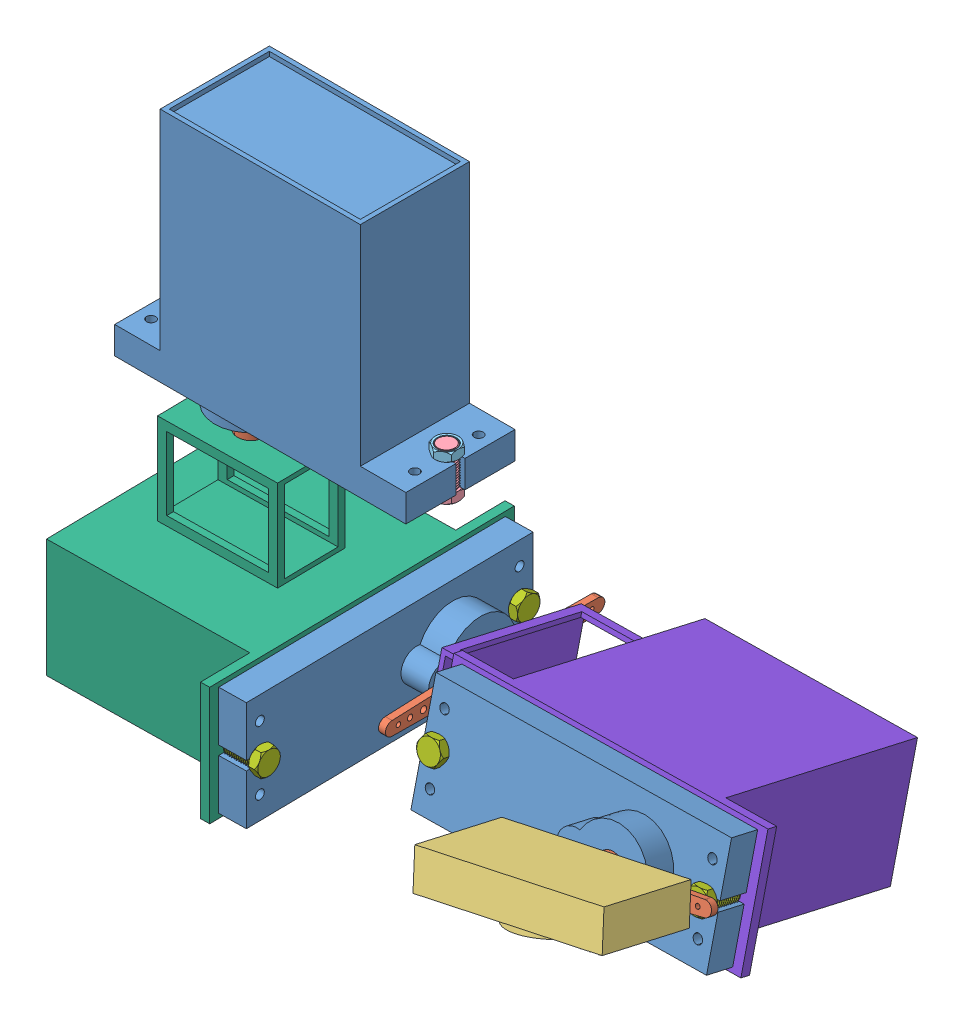
SolidWorks assembly ggimbal_assem, configuration Default. Lengths in mm.
Overall size (73.77 56.88 42.41).
21 component instances, 8 part files, 41 mates.
Components (placement in the parent):
- servo_body-1: servo_body [Default] at (-27.6645 3.5088 -0.9935) x (-0.015077 -0.232674 -0.972438) z (0.99988 0 -0.015503) size (31 12 32)
- servo_blade-1: servo_blade [Default] at (-9.4028 7.5806 15.7451) x (0.984245 0.167894 -0.055432) z (0.015077 0.232674 0.972438) size (24.5 3 2.5)
- camera_scaled-1: camera_scaled [Default] at (-9.3783 7.9587 17.3253) x (0.984245 0.167894 -0.055432) z (0.015077 0.232674 0.972438) size (20 5 10)
- servo_blade-2: servo_blade [Default] at (-40.6704 3.3925 -1.2782) x (0.015503 0 0.99988) z (0.99988 0 -0.015503) size (24.5 3 2.5)
- servo_body-2: servo_body [Default] at (-57.8893 3.3925 16.9909) x (-0.99988 0 0.015503) z (-0.015503 0 -0.99988) size (31 12 32)
- servo_blade-3: servo_blade [Default] at (-58.5598 22.3925 6) x (1 0 0) z (0 -1 0) size (24.5 3 2.5)
- servo_body-3: servo_body [Default] at (-40.5598 39.8925 6) x (0 1 0) z (-1 0 0) size (31 12 32)
- servo_bolt-3: servo_bolt [Default] at (-37.0598 25.3925 6) x (0 0 -1) z (0 -1 0) size (3.17 2.5 5.1)
- servo_bolt-4: servo_bolt [Default] at (-66.0598 25.3925 6) x (0 0 -1) z (0 -1 0) size (3.17 2.5 5.1)
- servo_nut-3: servo_nut [Default] at (-37.0598 29.3925 6) x (0 0 1) z (0 -1 0) size (3.17 2.62 1.08)
- servo_nut-4: servo_nut [Default] at (-66.0598 29.3925 6) x (-1 0 0) z (0 -1 0) size (3.17 2.62 1.08)
- servo_housing1-1: servo_housing1 [Default] at (-69.5584 3.3925 6.1705) x (0 -1 0) z (0.99988 0 -0.015503) size (23 34 23)
- servo_bolt_long-1: servo_bolt_long [Default] at (-43.3368 3.3925 20.2657) x (0.015503 0 0.99988) z (0.99988 0 -0.015503) size (3.17 2.5 6.11)
- servo_bolt_long-2: servo_bolt_long [Default] at (-43.7863 3.3925 -8.7308) x (0 1 0) z (0.99988 0 -0.015503) size (3.17 2.5 6.11)
- servo_nut-5: servo_nut [Default] at (-48.3362 3.3925 20.3432) x (0 1 0) z (0.99988 0 -0.015503) size (3.17 2.62 1.08)
- servo_nut-6: servo_nut [Default] at (-48.7857 3.3925 -8.6533) x (0 1 0) z (0.99988 0 -0.015503) size (3.17 2.62 1.08)
- servo_housing2-1: servo_housing2 [Default] at (-16.8392 0.8331 -12.3471) x (0.003607 -0.972555 0.232646) z (0.015077 0.232674 0.972438) size (13 38.5 23)
- servo_bolt_long-3: servo_bolt_long [Default] at (-30.9454 6.8826 13.1611) x (0.99988 0 -0.015503) z (0.015077 0.232674 0.972438) size (3.17 2.5 6.11)
- servo_bolt_long-4: servo_bolt_long [Default] at (-1.9489 6.8826 12.7115) x (0.99988 0 -0.015503) z (0.015077 0.232674 0.972438) size (3.17 2.5 6.11)
- servo_nut-7: servo_nut [Default] at (-31.0208 5.7192 8.2989) x (0.99988 0 -0.015503) z (0.015077 0.232674 0.972438) size (3.17 2.62 1.08)
- servo_nut-8: servo_nut [Default] at (-2.0243 5.7192 7.8493) x (0.99988 0 -0.015503) z (0.015077 0.232674 0.972438) size (3.17 2.62 1.08)
Mates (geometry in assembly coordinates):
- Concentric1: concentric aligned: cylinder of servo_body-1 through (-9.3726 8.046 17.69) axis (-0.015077 -0.232674 -0.972438) radius 1; cylinder of servo_blade-1 through (-9.3726 8.046 17.69) axis (-0.015077 -0.232674 -0.972438) radius 1
- Coincident1: coincident anti-aligned: plane of servo_body-1 through (-11.4025 7.5806 15.7761) normal (0.015077 0.232674 0.972438); plane of servo_blade-1 through (-9.4028 7.5806 15.7451) normal (-0.015077 -0.232674 -0.972438)
- Coincident60: coincident anti-aligned: line of servo_blade-1 through (-21.4353 5.902 18.0043) axis (0.984245 0.167894 -0.055432); line of camera_scaled-1 through (0.4642 9.6376 16.771) axis (-0.984245 -0.167894 0.055432)
- Coincident61: coincident anti-aligned: line of servo_blade-1 through (-9.6425 9.3956 16.9856) axis (0.176164 -0.957953 0.226477); line of camera_scaled-1 through (-9.0259 6.0428 17.7782) axis (-0.176164 0.957953 -0.226477)
- Coincident10: coincident anti-aligned: plane of servo_blade-1 through (1.9406 9.8895 16.6878) normal (0.015077 0.232674 0.972438); plane of camera_scaled-1 through (-9.3783 7.9587 17.3253) normal (-0.015077 -0.232674 -0.972438)
- Concentric3: concentric aligned: cylinder of servo_blade-2 through (-38.6707 3.3925 -1.3092) axis (-0.99988 0 0.015503) radius 1; cylinder of servo_body-2 through (-38.6707 3.3925 -1.3092) axis (-0.99988 0 0.015503) radius 1
- Coincident35: coincident anti-aligned: plane of servo_blade-2 through (-40.6704 3.3925 -1.2782) normal (-0.99988 0 0.015503); plane of servo_body-2 through (-40.6394 3.3925 0.7215) normal (0.99988 0 -0.015503)
- Concentric4: concentric aligned: cylinder of servo_blade-3 through (-58.5598 20.3925 6) axis (0 1 0) radius 1; cylinder of servo_body-3 through (-58.5598 20.3925 6) axis (0 1 0) radius 1
- Coincident36: coincident anti-aligned: plane of servo_blade-3 through (-58.5598 22.3925 6) normal (0 1 0); plane of servo_body-3 through (-56.5598 22.3925 6) normal (0 -1 0)
- Coincident47: coincident aligned: line of servo_body-3 through (-35.5598 25.3925 6) axis (-1 0 0); line of servo_bolt-3 through (-35.8098 25.3925 6) axis (-1 0 0)
- Coincident48: coincident anti-aligned: line of servo_body-3 through (-37.0598 25.3925 5) axis (0 0 1); line of servo_bolt-3 through (-37.0598 25.3925 7.4434) axis (0 0 -1)
- Coincident49: coincident aligned: line of servo_bolt-3 through (-37.0598 29.3925 4.5566) axis (0 0 1); line of servo_nut-3 through (-37.0598 29.3925 4.5566) axis (0 0 1)
- Coincident50: coincident aligned: line of servo_bolt-3 through (-35.8098 29.3925 6) axis (-1 0 0); line of servo_nut-3 through (-35.8098 29.3925 6) axis (-1 0 0)
- Coincident52: coincident anti-aligned: line of servo_body-3 through (-67.5598 25.3925 6) axis (1 0 0); line of servo_bolt-4 through (-64.8098 25.3925 6) axis (-1 0 0)
- Coincident53: coincident anti-aligned: line of servo_body-3 through (-66.0598 25.3925 5) axis (0 0 1); line of servo_bolt-4 through (-66.0598 25.3925 7.4434) axis (0 0 -1)
- Coincident54: coincident anti-aligned: line of servo_bolt-4 through (-66.0598 29.3925 4.5566) axis (0 0 1); line of servo_nut-4 through (-66.0598 29.3925 7.25) axis (0 0 -1)
- Coincident55: coincident aligned: line of servo_bolt-4 through (-64.8098 29.3925 6) axis (-1 0 0); line of servo_nut-4 through (-64.6164 29.3925 6) axis (-1 0 0)
- Coincident56: coincident anti-aligned: plane of servo_body-2 through (-57.8893 3.3925 16.9909) normal (0.015503 0 0.99988); plane of servo_housing1-1 through (-46.3897 9.3925 16.8126) normal (-0.015503 0 -0.99988)
- Coincident57: coincident anti-aligned: plane of servo_body-2 through (-46.7317 -2.6075 -5.1847) normal (0 -1 0); plane of servo_housing1-1 through (-46.7307 -2.6075 -5.1847) normal (0 1 0)
- Coincident58: coincident aligned: plane of servo_body-2 through (-69.729 9.3925 -4.8281) normal (-0.99988 0 0.015503); plane of servo_housing1-1 through (-69.5584 3.3925 6.1705) normal (-0.99988 0 0.015503)
- Coincident59: coincident anti-aligned: circle of servo_blade-3; circle of servo_housing1-1
- Coincident62: coincident anti-aligned: line of servo_body-2 through (-43.3135 3.3925 21.7655) axis (-0.015503 0 -0.99988); line of servo_bolt_long-1 through (-43.3591 3.3925 18.8225) axis (0.015503 0 0.99988)
- Coincident63: coincident anti-aligned: line of servo_body-2 through (-43.3368 4.3925 20.2657) axis (0 -1 0); line of servo_bolt_long-1 through (-43.3368 2.1425 20.2657) axis (0 1 0)
- Coincident64: coincident anti-aligned: line of servo_body-2 through (-43.7863 4.3925 -8.7308) axis (0 -1 0); line of servo_bolt_long-2 through (-43.7863 1.9491 -8.7308) axis (0 1 0)
- Coincident65: coincident anti-aligned: line of servo_body-2 through (-43.8096 3.3925 -10.2306) axis (0.015503 0 0.99988); line of servo_bolt_long-2 through (-43.767 3.3925 -7.481) axis (-0.015503 0 -0.99988)
- Coincident66: coincident anti-aligned: line of servo_bolt_long-2 through (-48.7664 3.3925 -7.4034) axis (-0.015503 0 -0.99988); line of servo_nut-6 through (-48.8051 3.3925 -9.9031) axis (0.015503 0 0.99988)
- Coincident67: coincident anti-aligned: line of servo_bolt_long-2 through (-48.7857 4.8359 -8.6533) axis (0 -1 0); line of servo_nut-6 through (-48.7857 1.9491 -8.6533) axis (0 1 0)
- Coincident68: coincident anti-aligned: line of servo_bolt_long-1 through (-48.3138 3.3925 21.7864) axis (-0.015503 0 -0.99988); line of servo_nut-5 through (-48.3555 3.3925 19.0934) axis (0.015503 0 0.99988)
- Coincident69: coincident aligned: line of servo_bolt_long-1 through (-48.3362 2.1425 20.3432) axis (0 1 0); line of servo_nut-5 through (-48.3362 1.9491 20.3432) axis (0 1 0)
- Coincident70: coincident anti-aligned: plane of servo_body-1 through (-5.4721 0.3492 11.2443) normal (0.003607 -0.972555 0.232646); plane of servo_housing2-1 through (-5.4721 0.3495 11.2453) normal (-0.003607 0.972555 -0.232646)
- Coincident71: coincident anti-aligned: plane of servo_body-1 through (-27.6645 3.5088 -0.9935) normal (-0.99988 0 0.015503); plane of servo_housing2-1 through (-27.5127 12.0201 8.7946) normal (0.99988 0 -0.015503)
- Coincident72: coincident aligned: plane of servo_body-1 through (-5.8621 6.6684 -13.9135) normal (-0.015077 -0.232674 -0.972438); plane of servo_housing2-1 through (-16.8392 0.8331 -12.3471) normal (-0.015077 -0.232674 -0.972438)
- Coincident73: coincident aligned: line of servo_body-1 through (-32.4452 6.8826 13.1843) axis (0.99988 0 -0.015503); line of servo_bolt_long-3 through (-32.3886 6.8826 13.1835) axis (0.99988 0 -0.015503)
- Coincident74: coincident aligned: line of servo_body-1 through (-30.949 7.8552 12.9284) axis (0.003607 -0.972555 0.232646); line of servo_bolt_long-3 through (-30.9499 8.0983 12.8703) axis (0.003607 -0.972555 0.232646)
- Coincident75: coincident aligned: line of servo_body-1 through (-1.9525 7.8552 12.4788) axis (0.003607 -0.972555 0.232646); line of servo_bolt_long-4 through (-1.9534 8.0983 12.4207) axis (0.003607 -0.972555 0.232646)
- Coincident76: coincident anti-aligned: line of servo_body-1 through (-0.4491 6.8826 12.6882) axis (-0.99988 0 0.015503); line of servo_bolt_long-4 through (-3.3921 6.8826 12.7339) axis (0.99988 0 -0.015503)
- Coincident77: coincident anti-aligned: line of servo_bolt_long-3 through (-29.5776 5.7192 8.2765) axis (-0.99988 0 0.015503); line of servo_nut-7 through (-32.464 5.7192 8.3213) axis (0.99988 0 -0.015503)
- Coincident78: coincident anti-aligned: line of servo_bolt_long-3 through (-31.0253 6.9349 8.0081) axis (0.003607 -0.972555 0.232646); line of servo_nut-7 through (-31.0163 4.5035 8.5897) axis (-0.003607 0.972555 -0.232646)
- Coincident79: coincident anti-aligned: line of servo_bolt_long-4 through (-0.5811 5.7192 7.8269) axis (-0.99988 0 0.015503); line of servo_nut-8 through (-3.4675 5.7192 7.8717) axis (0.99988 0 -0.015503)
- Coincident80: coincident anti-aligned: line of servo_bolt_long-4 through (-2.0288 6.9349 7.5585) axis (0.003607 -0.972555 0.232646); line of servo_nut-8 through (-2.0198 4.5035 8.1401) axis (-0.003607 0.972555 -0.232646)
- Coincident81: coincident anti-aligned: circle of servo_blade-2; circle of servo_housing2-1
